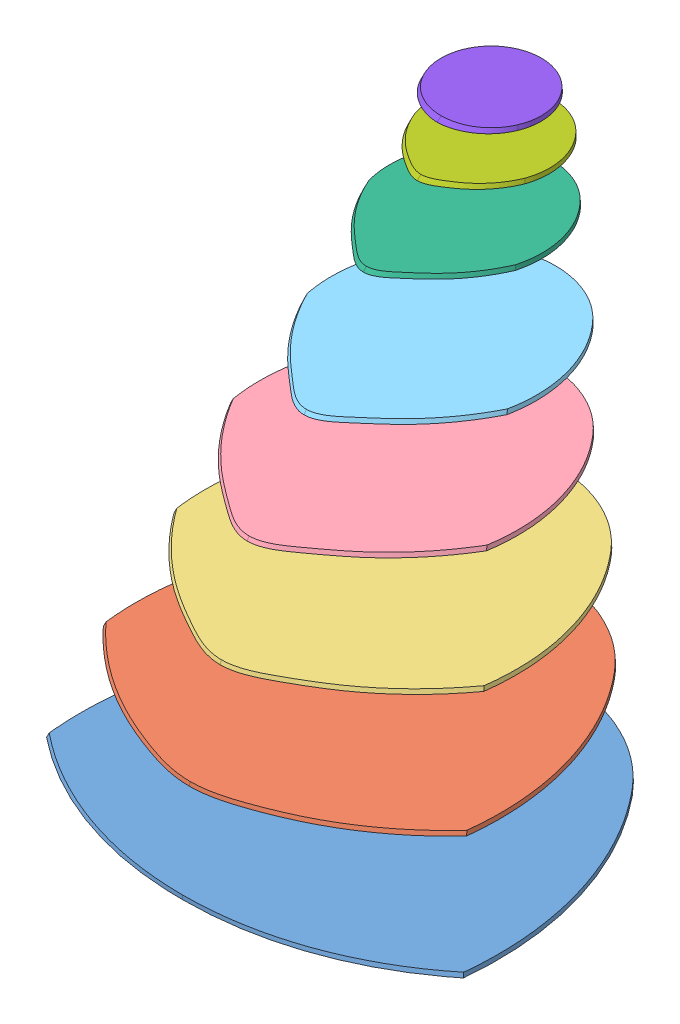
SolidWorks assembly rib Assembly, configuration Default. Lengths in mm.
Overall size (392.89 464.19 360.25).
8 component instances, 8 part files, 7 mates.
Components (placement in the parent):
- Rib1-1: Rib1 [Default] at (9.5874 250.6633 468.4617) size (392.89 3.67 360.25)
- Rib2-1: Rib2 [Default] at (3.7742 250.6633 469.6462) size (364.49 90.1 343.04)
- Rib3-1: Rib3 [Default] at (2.0647 250.6633 462.7785) size (364.49 173.47 337.83)
- Rib4-1: Rib4 [Default] at (-2.8528 250.6633 465.121) size (364.49 253.01 334.6)
- Rib5-1: Rib5 [Default] at (3.1879 250.6633 463.1417) size (364.49 327.9 332.72)
- Rib6-1: Rib6 [Default] at (-2.1067 250.6633 460.5073) size (364.49 397.34 328.58)
- Rib7-1: Rib7 [Default] at (3.2835 250.6633 464.1934) size (364.49 440.21 328.58)
- Rib8-1: Rib8 [Default] at (-2.707 253.8383 467.4945) size (364.49 461.01 328.58)
Mates (geometry in assembly coordinates):
- Distance1: distance = 76.2 mm aligned: plane of Rib1-1 through (104.9662 250.6633 490.5934) normal (0 -1 0); plane of Rib2-1 through (-178.958 326.8633 178.8979) normal (0 -1 0)
- Distance2: distance = 76.2 mm aligned: plane of Rib2-1 through (-178.958 326.8633 178.8979) normal (0 -1 0); plane of Rib3-1 through (-180.6675 403.0633 172.0302) normal (0 -1 0)
- Distance3: distance = 76.2 mm aligned: plane of Rib3-1 through (-180.6675 403.0633 172.0302) normal (0 -1 0); plane of Rib4-1 through (-185.585 479.2633 174.3727) normal (0 -1 0)
- Distance4: distance = 76.2 mm aligned: plane of Rib5-1 through (-179.5443 555.4633 172.3935) normal (0 -1 0); plane of Rib4-1 through (-185.585 479.2633 174.3727) normal (0 -1 0)
- Distance5: distance = 76.2 mm aligned: plane of Rib5-1 through (-179.5443 555.4633 172.3935) normal (0 -1 0); plane of Rib6-1 through (-184.8389 631.6633 169.759) normal (0 -1 0)
- Distance6: distance = 50.8 mm aligned: plane of Rib6-1 through (-184.8389 631.6633 169.759) normal (0 -1 0); plane of Rib7-1 through (-179.4487 682.4633 173.4452) normal (0 -1 0)
- Distance7: distance = 29.21 mm aligned: plane of Rib8-1 through (-185.4392 711.6733 467.4945) normal (0 -1 0); plane of Rib7-1 through (-179.4487 682.4633 173.4452) normal (0 -1 0)
